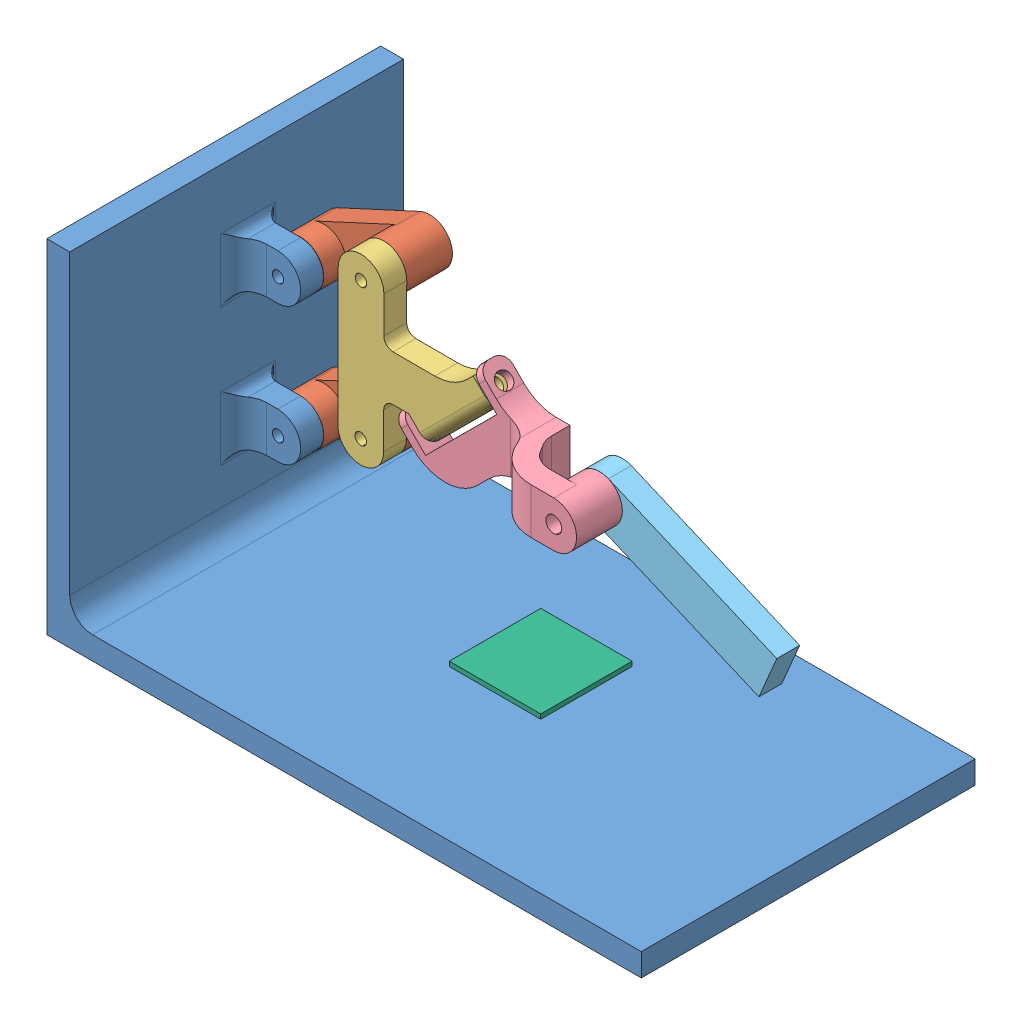
SolidWorks assembly TR4Assieme1, configuration Default. Lengths in mm.
Overall size (130 75 73).
7 component instances, 6 part files, 13 mates.
Components (placement in the parent):
- TR4basemat-1: TR4basemat [Default] at origin size (130 75 73)
- TR4link1-2: TR4link1 [Default] at (14.6854 53.3577 20) x (0.907862 0.419269 0) z (0 0 1) size (30 10 10)
- TR4link1-3: TR4link1 [Default] at (14.6631 23.284 20) x (0.90503 0.425349 0) z (0 0 1) size (30 10 10)
- TR4link2-1: TR4link2 [Default] at (25.6731 41.6547 30) x (0.001888 0.999998 0) z (0 0 1) size (40 33.79 10)
- TR4link3-1: TR4link3 [Default] at (65.8753 38.3708 29.5) x (0.999998 -0.001888 0) z (0 0 1) size (49.6 25.56 15.5)
- TR4link4-1: TR4link4 [Default] at (96.0662 35.0651 35) x (0.920258 -0.391313 0) z (0 0 -1) size (45 10 10)
- TR4oggetto-1: TR4oggetto [Default] at (60 1 30) x (1 0 0) z (0 -1 0) size (20 20 1)
Mates (geometry in assembly coordinates):
- Coincidente7: coincident anti-aligned: plane of TR4base-1 through (0 0 0) normal (0 1 0); plane of oggetto-1 through (60 0 30) normal (0 -1 0)
- Distanza2: distance = 55 mm aligned: plane of oggetto-1 through (70 0 40) normal (1 0 0); plane of TR4base-1 through (125 -5 0) normal (1 0 0)
- Concentrico8: concentric aligned: cylinder of TR4link2-1 through (34.8877 33.1085 32.5) axis (0.708441 0.70577 0) radius 1.65; cylinder of TR4link3-1 through (36.777 34.9907 32.5) axis (0.708441 0.70577 0) radius 1.75
- Concentrico9: concentric aligned: cylinder of TR4link1-2 through (25.7048 58.4467 20) axis (0 0 1) radius 1.75; cylinder of TR4link2-1 through (25.7048 58.4467 25) axis (0 0 1) radius 2.5
- Concentrico10: concentric anti-aligned: cylinder of TR4base-1 through (7.5476 50.0613 70) axis (0 0 -1) radius 1.25; cylinder of TR4link1-2 through (7.5476 50.0613 20) axis (0 0 1) radius 1.75
- Coincidente10: coincident anti-aligned: plane of TR4link1-2 through (25.7048 58.4467 30) normal (0 0 1); plane of TR4link2-1 through (25.6482 28.4467 30) normal (0 0 -1)
- Concentrico11: concentric anti-aligned: cylinder of TR4link1-3 through (25.6482 28.4467 20) axis (0 0 1) radius 1.75; cylinder of TR4link2-1 through (25.6482 28.4467 35) axis (0 0 -1) radius 1.25
- Concentrico12: concentric anti-aligned: cylinder of TR4base-1 through (7.5476 19.9398 70) axis (0 0 -1) radius 1.25; cylinder of TR4link1-3 through (7.5476 19.9398 20) axis (0 0 1) radius 1.75
- Coincidente11: coincident anti-aligned: plane of TR4link1-3 through (25.6482 28.4467 30) normal (0 0 1); plane of TR4link2-1 through (25.6482 28.4467 30) normal (0 0 -1)
- Parallelo3: parallel aligned: plane of TR4link2-1 through (25.6482 28.4467 30) normal (0 0 -1); plane of TR4link3-1 through (75.8847 43.3519 29.5) normal (0 0 -1)
- Coincidente15: coincident aligned: plane of TR4link2-1 through (30.6859 48.4373 35) normal (0.001888 0.999998 0); plane of TR4link3-1 through (55.8942 48.3897 35.5) normal (0.001888 0.999998 0)
- Concentrico13: concentric anti-aligned: cylinder of TR4link3-1 through (77.8553 43.3482 35) axis (0 0 1) radius 2.6; cylinder of TR4link4-1 through (77.8553 43.3482 40) axis (0 0 -1) radius 2.5
- Coincidente16: coincident anti-aligned: plane of TR4link3-1 through (65.8753 38.3708 35) normal (0 0 -1); plane of TR4link4-1 through (77.8553 43.3482 35) normal (0 0 1)
